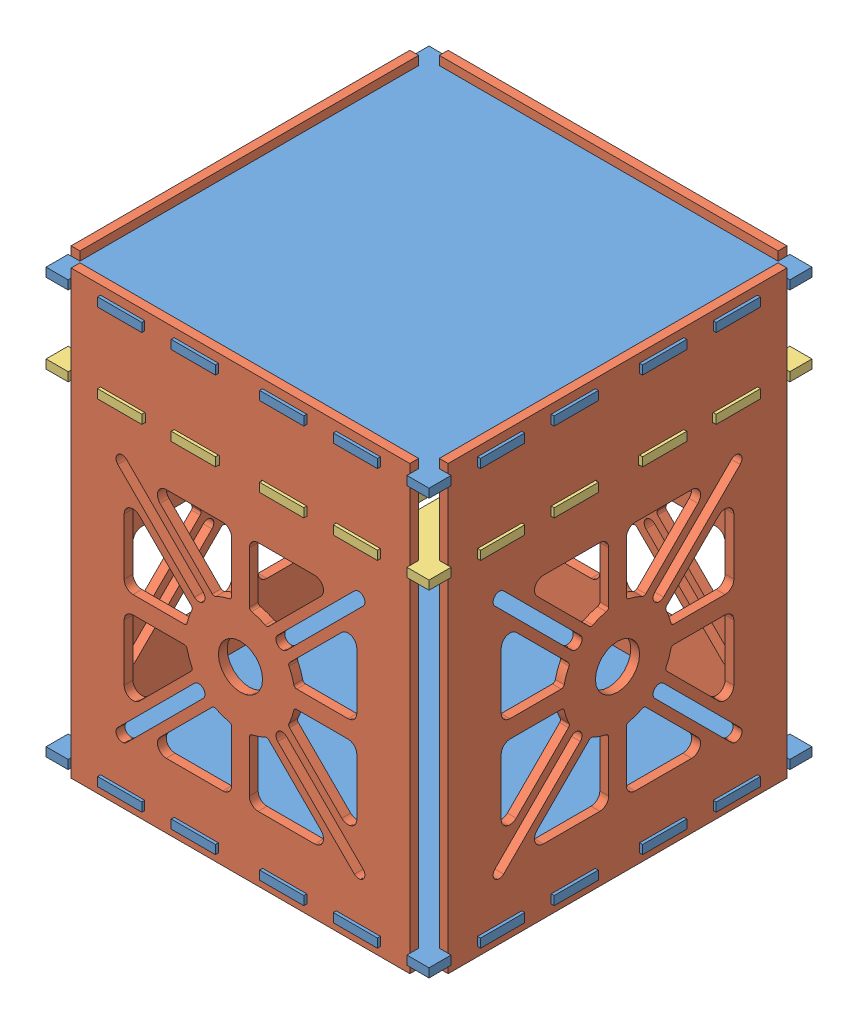
SolidWorks assembly final, configuration Default. Lengths in mm.
Overall size (130 150 130).
7 component instances, 3 part files, 18 mates.
Components (placement in the parent):
- shelve-1: shelve [Default] at (1.0656 79.36 115.9852) size (130 3 130)
- sides-1: sides [Default] at (65.0656 10.36 115.9852) x (0 0 1) z (-1 0 0) size (115 150 3)
- sides-2: sides [Default] at (-62.9344 10.36 115.9852) x (0 0 -1) z (1 0 0) size (115 150 3)
- sides-3: sides [Default] at (1.0656 10.36 176.9852) size (115 150 3)
- sides-4: sides [Default] at (1.0656 10.36 51.9852) size (115 150 3)
- shelve-7: shelve [Default] at (1.0656 -61.64 115.9852) size (130 3 130)
- shelve - Copy-1: shelve - Copy [Default] at (1.0656 52.36 115.9852) size (130 3 130)
Mates (geometry in assembly coordinates):
- Coincident1: coincident: plane of assembly; plane of assembly; plane of shelve-1 through (1.0656 82.36 115.9852) normal (0 1 0); plane of sides-3 through (-21.4344 82.36 179.9852) normal (0 -1 0)
- Coincident2: coincident: plane of assembly; plane of assembly; plane of shelve-1 through (-56.4344 82.36 180.9852) normal (1 0 0); plane of sides-3 through (-56.4344 85.36 179.9852) normal (-1 0 0)
- Coincident3: coincident: plane of assembly; plane of assembly; plane of shelve-1 through (-56.4344 82.36 176.9852) normal (0 0 1); plane of sides-3 through (1.0656 10.36 176.9852) normal (0 0 -1)
- Coincident4: coincident: plane of assembly; plane of assembly; plane of sides-3 through (1.0656 10.36 176.9852) normal (0 0 -1); plane of shelve-7 through (-56.4344 -58.64 176.9852) normal (0 0 1)
- Coincident5: coincident: plane of assembly; plane of assembly; plane of sides-3 through (58.5656 85.36 179.9852) normal (1 0 0); plane of shelve-7 through (58.5656 -58.64 180.9852) normal (-1 0 0)
- Coincident6: coincident: plane of assembly; plane of assembly; plane of sides-3 through (-46.4344 -58.64 179.9852) normal (0 -1 0); plane of shelve-7 through (1.0656 -58.64 115.9852) normal (0 1 0)
- Coincident12: coincident: plane of assembly; plane of assembly; plane of shelve-1 through (62.0656 82.36 138.4852) normal (1 0 0); plane of sides-1 through (62.0656 10.36 115.9852) normal (-1 0 0)
- Coincident13: coincident: plane of assembly; plane of assembly; plane of shelve-1 through (62.0656 82.36 173.4852) normal (0 0 -1); plane of sides-1 through (62.0656 85.36 173.4852) normal (0 0 1)
- Coincident14: coincident: plane of assembly; plane of assembly; plane of shelve-1 through (1.0656 82.36 115.9852) normal (0 1 0); plane of sides-1 through (62.0656 82.36 163.4852) normal (0 -1 0)
- Coincident15: coincident: plane of assembly; plane of assembly; plane of shelve-1 through (1.0656 82.36 115.9852) normal (0 1 0); plane of sides-4 through (48.5656 82.36 54.9852) normal (0 -1 0)
- Coincident16: coincident: plane of assembly; plane of assembly; plane of shelve-1 through (58.5656 82.36 50.9852) normal (-1 0 0); plane of sides-4 through (58.5656 85.36 54.9852) normal (1 0 0)
- Coincident17: coincident: plane of assembly; plane of assembly; plane of shelve-1 through (-6.4344 82.36 54.9852) normal (0 0 -1); plane of sides-4 through (1.0656 10.36 54.9852) normal (0 0 1)
- Coincident18: coincident: plane of assembly; plane of assembly; plane of shelve-1 through (-59.9344 82.36 93.4852) normal (-1 0 0); plane of sides-2 through (-59.9344 10.36 115.9852) normal (1 0 0)
- Coincident19: coincident: plane of assembly; plane of assembly; plane of shelve-1 through (1.0656 82.36 115.9852) normal (0 1 0); plane of sides-2 through (-59.9344 82.36 93.4852) normal (0 -1 0)
- Coincident20: coincident: plane of assembly; plane of assembly; plane of shelve-1 through (-59.9344 82.36 173.4852) normal (0 0 -1); plane of sides-2 through (-59.9344 85.36 173.4852) normal (0 0 1)
- Coincident21: coincident: plane of assembly; plane of assembly; plane of sides-3 through (48.2656 55.36 179.9852) normal (0 -1 0); plane of shelve - Copy-1 through (1.0656 55.36 115.9852) normal (0 1 0)
- Coincident22: coincident: plane of assembly; plane of assembly; plane of sides-3 through (58.5656 85.36 179.9852) normal (1 0 0); plane of shelve - Copy-1 through (58.5656 55.36 180.9852) normal (-1 0 0)
- Coincident23: coincident: plane of assembly; plane of assembly; plane of sides-3 through (1.0656 10.36 176.9852) normal (0 0 -1); plane of shelve - Copy-1 through (58.5656 55.36 176.9852) normal (0 0 1)
